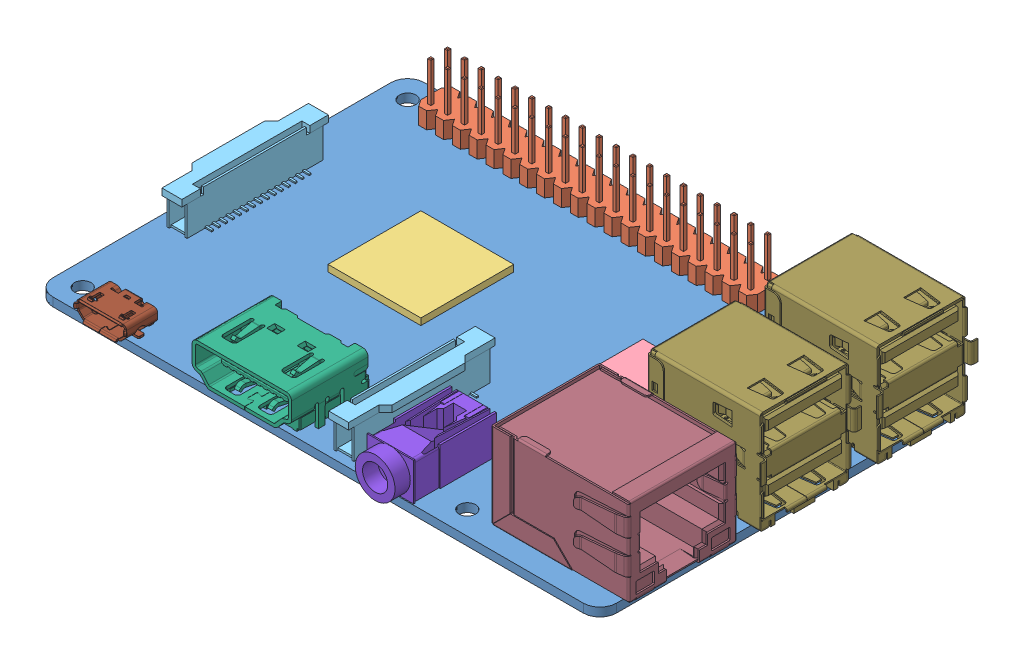
SolidWorks assembly RaspberryPi2 model B SW, configuration Default. Lengths in mm.
Overall size (89.62 24.59 58.3).
15 component instances, 13 part files, 43 mates.
Components (placement in the parent):
- Mainboard2-1: Mainboard2 [Default] at origin size (85 1.3 56)
- GPIO-1: GPIO [Default] at (-11.37 0 -24.5) x (0 0 1) z (-1 0 0) size (5 11.5 50.8)
- Processor-1: Processor [Default] at (-15.5 0 -3) x (0 0 1) z (-1 0 0) size (14 1 14)
- GPU-1: GPU [Default] at (15.25 0 -5.75) x (0 0 1) z (-1 0 0) size (9.1 1 9.1)
- CameraAssembly-4: CameraAssembly [Default] at (10.0885 -2.9159 16.55) x (-1 0 0) z (0 0 -1) size (5 5.5 22.1)
- CameraAssembly-3: CameraAssembly [Default] at (-46.3885 -2.9159 0) size (5 5.5 22.1)
- hdmi-1: hdmi [Default] at (-10.2 0.27 29.3) size (15.14 8.38 12.15)
- RAM-1: RAM [Default] at (0.5 -2.3 -6) x (0 0 1) z (-1 0 0) size (12 1 12)
- Audio-1: Audio [Default] at (10.9 0.15 21.75) size (7 6 14.8)
- MicroSDSocket-1: MicroSDSocket [Default] at (-34.5 -1.3 -0.7) x (0 0 -1) z (-1 0 0) size (13 1.3 14)
- MicroSD-1: MicroSD [Default] at (-37 -2.3 0.1) x (0 0 1) z (-1 0 0) size (11 1 15)
- micro USB2-1: micro USB2 [Default] at (-17.2704 -5.0969 44.9026) size (7.99 2.94 5.43)
- usb double-1: usb double [Default] at (30.38 -0.09 -18.85) x (0 0 -1) z (1 0 0) size (15.6 18.75 17.92)
- usb double-2: usb double [Default] at (30.38 -0.09 -1.25) x (0 0 -1) z (1 0 0) size (15.6 18.75 17.92)
- RJ45-LED-1: RJ45-LED [Default] at (34.11 7.4 17.348) x (1 0 0) z (0 -1 0) size (20.75 17.99 14.09)
Mates (geometry in assembly coordinates):
- Coincidente19: coordinate: point of Mainboard2-1; point of assembly
- Distanza16: distance = 2.3 mm aligned: plane of Audio-1 through (10.9 6 30.3) normal (0 0 1); plane of Mainboard2-1 through (-40 -1.3 28) normal (0 0 1)
- Distanza17: distance = 28.1 mm aligned: plane of Audio-1 through (14.4 0.15 28) normal (1 0 0); plane of Mainboard2-1 through (42.5 -1.3 25.5) normal (1 0 0)
- Distanza20: distance = 6.5 mm aligned: plane of hdmi-1 through (-4.6 6.5 17.85) normal (0 1 0); plane of Mainboard2-1 through (40 0 25.5) normal (0 1 0)
- Distanza27: distance = 0.1 mm anti-aligned: plane of MicroSD-1 through (-37.1747 -2.3 0.1936) normal (0 -1 0); plane of MicroSDSocket-1 through (-34.5 -2.4 -0.7) normal (0 1 0)
- Coincidente39: coincident anti-aligned: plane of MicroSDSocket-1 through (-27.5 -1.3 5.6) normal (0 0 -1); plane of MicroSD-1 through (-44.5 -2.3 5.6) normal (0 0 1)
- Distanza28: distance = 3 mm aligned: plane of MicroSD-1 through (-44.5 -2.3 -5.4) normal (-1 0 0); plane of MicroSDSocket-1 through (-41.5 -1.3 5.8) normal (-1 0 0)
- Coincidente41: coincident anti-aligned: plane of Mainboard2-1 through (40 -1.3 25.5) normal (0 -1 0); plane of MicroSDSocket-1 through (-34.5 -1.3 -0.7) normal (0 1 0)
- Distanza29: distance = 1 mm aligned: plane of MicroSDSocket-1 through (-41.5 -1.3 5.8) normal (-1 0 0); plane of Mainboard2-1 through (-42.5 -1.3 -25.5) normal (-1 0 0)
- Distanza30: distance = 20.8 mm aligned: plane of MicroSDSocket-1 through (-41.5 -1.3 -7.2) normal (0 0 -1); plane of Mainboard2-1 through (40 -1.3 -28) normal (0 0 -1)
- Coincidente44: coincident anti-aligned: plane of Mainboard2-1 through (40 0 25.5) normal (0 1 0); plane of GPIO-1 through (-11.37 0 -24.5) normal (0 -1 0)
- Distanza31: distance = 7 mm aligned: plane of GPIO-1 through (-35.5 0 -26) normal (-1 0 0); plane of Mainboard2-1 through (-42.5 -1.3 -25.5) normal (-1 0 0)
- Distanza32: distance = 1 mm aligned: plane of GPIO-1 through (-33.63 0 -27) normal (0 0 -1); plane of Mainboard2-1 through (40 -1.3 -28) normal (0 0 -1)
- Coincidente47: coincident anti-aligned: plane of Mainboard2-1 through (40 0 25.5) normal (0 1 0); plane of Processor-1 through (-15.5 0 -3) normal (0 -1 0)
- Distanza33: distance = 18 mm aligned: plane of Processor-1 through (-8.5 0 -10) normal (0 0 -1); plane of Mainboard2-1 through (40 -1.3 -28) normal (0 0 -1)
- Distanza34: distance = 20 mm aligned: plane of Processor-1 through (-22.5 0 -10) normal (-1 0 0); plane of Mainboard2-1 through (-42.5 -1.3 -25.5) normal (-1 0 0)
- Coincidente50: coincident anti-aligned: plane of Mainboard2-1 through (40 -1.3 25.5) normal (0 -1 0); plane of RAM-1 through (0.5 -1.3 -6) normal (0 1 0)
- Distanza35: distance = 16 mm aligned: plane of RAM-1 through (6.5 -2.3 -12) normal (0 0 -1); plane of Mainboard2-1 through (40 -1.3 -28) normal (0 0 -1)
- Distanza36: distance = 37 mm aligned: plane of RAM-1 through (-5.5 -2.3 -12) normal (-1 0 0); plane of Mainboard2-1 through (-42.5 -1.3 -25.5) normal (-1 0 0)
- Coincidente53: coincident anti-aligned: plane of Mainboard2-1 through (40 0 25.5) normal (0 1 0); plane of GPU-1 through (15.25 0 -5.75) normal (0 -1 0)
- Distanza37: distance = 18 mm aligned: plane of GPU-1 through (19.5 0 -10) normal (0 0 -1); plane of Mainboard2-1 through (40 -1.3 -28) normal (0 0 -1)
- Distanza38: distance = 23 mm aligned: plane of GPU-1 through (19.5 0 -1.5) normal (1 0 0); plane of Mainboard2-1 through (42.5 -1.3 25.5) normal (1 0 0)
- Distanza39: distance = 1.3 mm aligned: plane of hdmi-1 through (-28.801 6 29.3) normal (0 0 1); plane of Mainboard2-1 through (-40 -1.3 28) normal (0 0 1)
- Distanza40: distance = 24.8 mm aligned: plane of hdmi-1 through (-17.7 18.8639 17.85) normal (-1 0 0); plane of Mainboard2-1 through (-42.5 -1.3 -25.5) normal (-1 0 0)
- Tangente2: tangent anti-aligned: plane of Mainboard2-1 through (40 0 25.5) normal (0 1 0); cylinder of Audio-1 through (10.9 3 29.15) axis (0 0 -1) radius 3
- Distanza43: distance = 2.6 mm anti-aligned: plane of micro USB2-1 through (-34.95 2.6 24.1941) normal (0 -1 0); plane of Mainboard2-1 through (40 0 25.5) normal (0 1 0)
- Distanza44: distance = 1.3 mm anti-aligned: cylinder of micro USB2-1 through (-29.25 0.0937 29.31) axis (-1 0 0) radius 0.01; plane of Mainboard2-1 through (-40 -1.3 28) normal (0 0 1)
- Distanza45: distance = 7 mm anti-aligned: plane of micro USB2-1 through (-35.5 1.3036 24.1941) normal (1 0 0); plane of Mainboard2-1 through (-42.5 -1.3 -25.5) normal (-1 0 0)
- Distanza46: distance = 15.5 mm aligned: plane of usb double-1 through (33.3225 15.5 -40.1817) normal (0 1 0); plane of Mainboard2-1 through (40 0 25.5) normal (0 1 0)
- Coincidente61: coincident aligned: plane of usb double-1 through (33.3225 15.5 -40.1817) normal (0 1 0); plane of usb double-2 through (33.3225 15.5 -22.5817) normal (0 1 0)
- Coincidente63: coincident aligned: plane of usb double-1 through (44.5 -0.09 -18.85) normal (1 0 0); plane of usb double-2 through (44.5 -0.09 -1.25) normal (1 0 0)
- Distanza47: distance = 2.5 mm aligned: plane of usb double-1 through (33.3225 0.4896 -25.5) normal (0 0 -1); plane of Mainboard2-1 through (40 -1.3 -28) normal (0 0 -1)
- Distanza48: distance = 4.3 mm anti-aligned: plane of usb double-2 through (33.3225 0.4896 -7.9) normal (0 0 -1); plane of usb double-1 through (33.3225 43.1529 -12.2) normal (0 0 1)
- Distanza49: distance = 14 mm aligned: plane of RJ45-LED-1 through (44.36 14 25.248) normal (0 1 0); plane of Mainboard2-1 through (40 0 25.5) normal (0 1 0)
- Distanza50: distance = 2 mm aligned: plane of usb double-2 through (44.5 -0.09 -1.25) normal (1 0 0); plane of Mainboard2-1 through (42.5 -1.3 25.5) normal (1 0 0)
- Coincidente68: coincident aligned: plane of usb double-2 through (44.36 -0.09 -1.25) normal (1 0 0); plane of RJ45-LED-1 through (44.36 0.8 25.248) normal (1 0 0)
- Distanza51: distance = 2.5 mm aligned: plane of RJ45-LED-1 through (34.11 7.4 25.5) normal (0 0 1); plane of Mainboard2-1 through (-40 -1.3 28) normal (0 0 1)
- Distanza52: distance = 3.2 mm anti-aligned: plane of Audio-1 through (7.4 0.15 15.5) normal (-1 0 0); plane of CameraAssembly-4 through (4.2 0 26.8) normal (1 0 0)
- Distanza53: distance = 1.2 mm aligned: plane of CameraAssembly-4 through (1.2 0 26.8) normal (0 0 1); plane of Mainboard2-1 through (-40 -1.3 28) normal (0 0 1)
- Coincidente72: coincident anti-aligned: plane of Mainboard2-1 through (40 0 25.5) normal (0 1 0); plane of CameraAssembly-4 through (2.7 0 16.55) normal (0 -1 0)
- Distanza54: distance = 2 mm aligned: plane of CameraAssembly-3 through (-40.5 0 -10.25) normal (-1 0 0); plane of Mainboard2-1 through (-42.5 -1.3 -25.5) normal (-1 0 0)
- Distanza55: distance = 17.75 mm: plane of CameraAssembly-3 through (-40.5 0 10.25) normal (0 0 1); line of Mainboard2-1 through (-40 0 28) axis (1 0 0)
- Coincidente75: coincident anti-aligned: plane of Mainboard2-1 through (40 0 25.5) normal (0 1 0); plane of CameraAssembly-3 through (-39 0 0) normal (0 -1 0)
